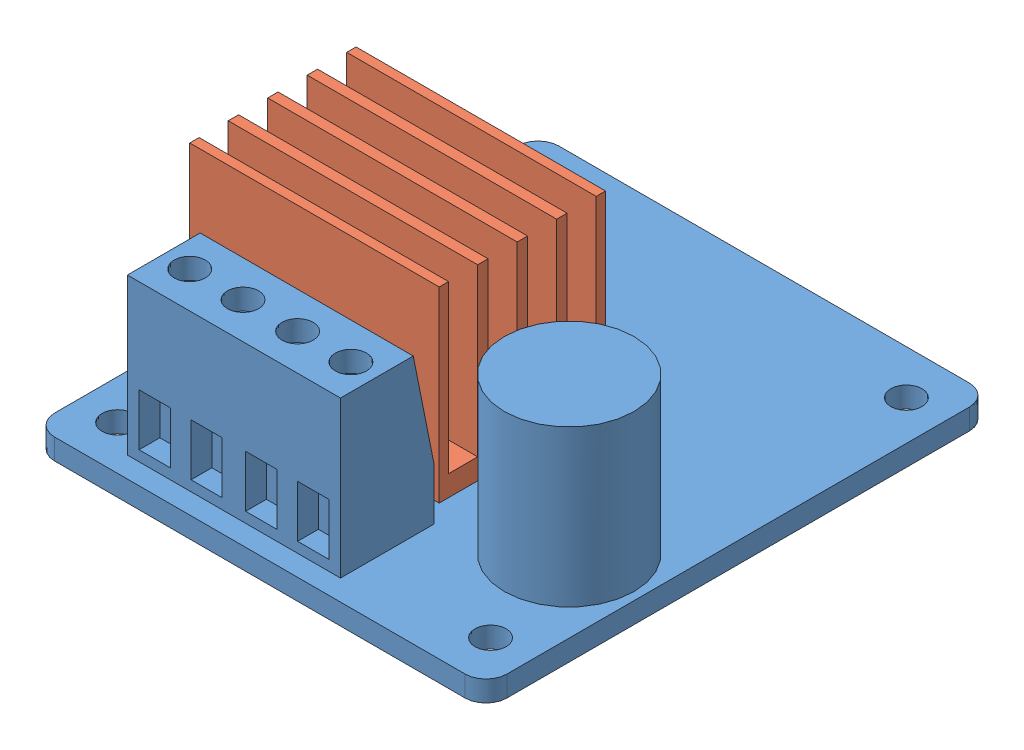
SolidWorks assembly ibt-3_assembly, configuration Default. Lengths in mm.
Overall size (43.5 20 48.5).
2 component instances, 2 part files, 4 mates.
Components (placement in the parent):
- Part12^ibt-3_assembly-1: Part12^ibt-3_assembly [Default] at origin size (43.5 17 48.5) (virtual)
- Part13^ibt-3_assembly-1: Part13^ibt-3_assembly [Default] at (0 2 0) x (1 0 0) z (0 1 0) size (24 16 18) (virtual)
Mates (geometry in assembly coordinates):
- InPlace1: in place: plane of Part12^ibt-3_assembly-1 through (0 2 0) normal (0 1 0); plane of Part13^ibt-3_assembly-1 through (0 2 0) normal (0 1 0); moOrthogonalPlaneRef_w of Part12^ibt-3_assembly-1 through (0 2 0) normal (0 1 0); plane of Part13^ibt-3_assembly-1 through (0 2 0) normal (0 0 -1); plane of Part12^ibt-3_assembly-1 through (0 2 0) normal (0 1 0); line of Part13^ibt-3_assembly-1 through (-55 0 2) axis (0 1 0); plane of Part12^ibt-3_assembly-1 through (0 2 0) normal (0 1 0); unknown of Part13^ibt-3_assembly-1
- Coincident1: coincident aligned: plane of Part12^ibt-3_assembly-1; plane of Part13^ibt-3_assembly-1
- Coincident2: coincident aligned: moOrthogonalPlaneRef_w of Part12^ibt-3_assembly-1 through (0 2 0) normal (0 0 -1); plane of Part13^ibt-3_assembly-1 through (0 2 0) normal (0 0 -1)
- Coincident3: coincident anti-aligned: moOrthogonalPlaneRef_w of Part12^ibt-3_assembly-1 through (0 2 0) normal (-1 0 0); plane of Part13^ibt-3_assembly-1
